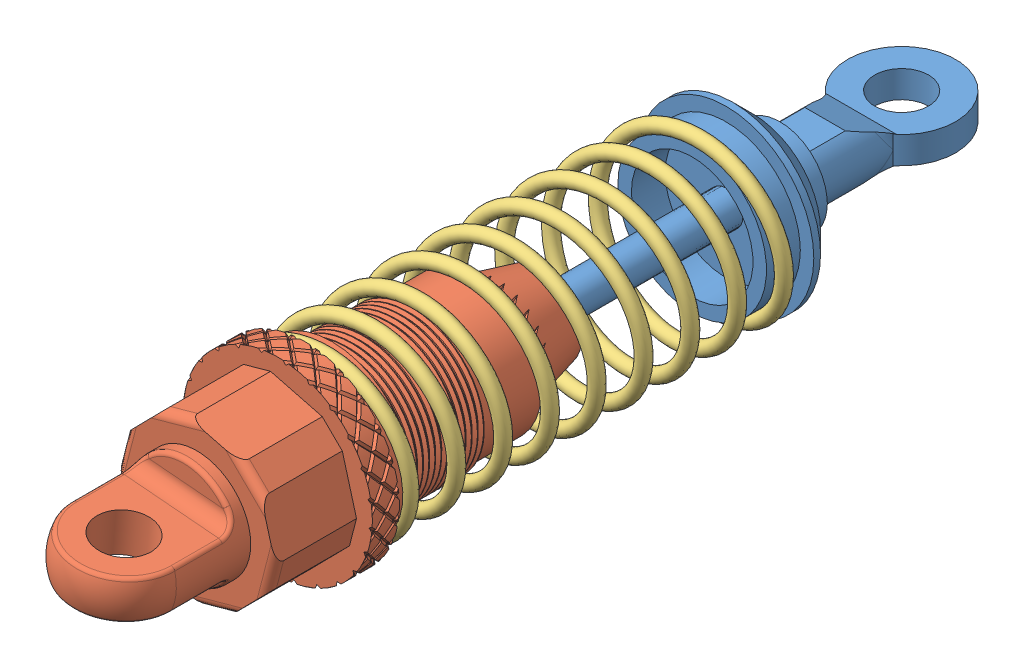
SolidWorks assembly coilover, configuration Default. Lengths in mm.
Overall size (15.15 15.15 65.67).
3 component instances, 3 part files, 3 mates.
Components (placement in the parent):
- strut bottom-1: strut bottom [Default] at (8.2738 19.4064 16.0769) size (13 13 37)
- strut top-1: strut top [Default] at (8.2738 20.4064 60.2501) x (0.996359 -0.085262 0) z (0.085262 0.996359 0) size (14.01 35 14.01)
- spring-1: spring [Default] at (8.2738 20.4064 29.0769) x (1 0 0) z (0 -1 0) size (13.4 33.17 15.01)
Mates (geometry in assembly coordinates):
- Concentric1: concentric anti-aligned: circle of strut bottom-1; circle of strut top-1
- Coincident2: coincident anti-aligned: plane of strut bottom-1 through (8.2738 19.4064 29.0769) normal (0 0 1); plane of spring-1 through (8.2738 20.4064 29.0769) normal (0 0 -1)
- Coincident3: coincident: point of strut bottom-1; point of spring-1
